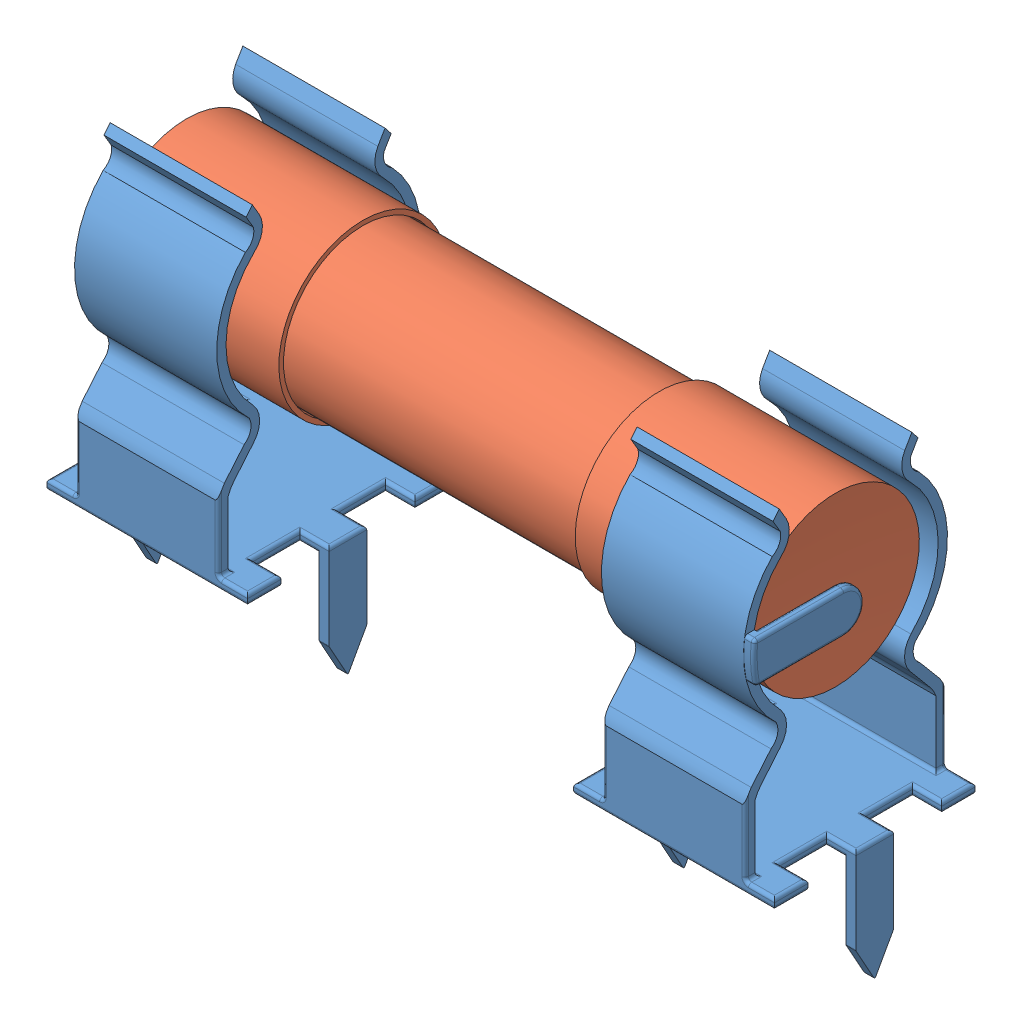
SolidWorks assembly SW3dPS-Full Fuse, configuration Default. Lengths in mm.
Overall size (22.1 12.9 6.21).
3 component instances, 2 part files, 8 mates.
Components (placement in the parent):
- SW3dPS-Full Fuse_Fuse Leg_2009-1: SW3dPS-Full Fuse_Fuse Leg_2009 [Default] at (8 0 0) x (1 0 0) z (0 1 0) size (6.1 6.2 12.9)
- SW3dPS-Full Fuse_Fuse Leg_2009-2: SW3dPS-Full Fuse_Fuse Leg_2009 [Default] at (-8 0 0) x (-1 0 0) z (0 1 0) size (6.1 6.2 12.9)
- SW3dPS-Full Fuse_Fuse Small 1A-1: SW3dPS-Full Fuse_Fuse Small 1A [Default] at (0 6.3 0) x (1 0 0) z (0 -1 0) size (19.91 5.21 5.19)
Mates (geometry in assembly coordinates):
- Distance1: distance = 16 mm anti-aligned: plane of SW3dPS-Full Fuse_Fuse Leg_2009-1; plane of SW3dPS-Full Fuse_Fuse Leg_2009-2
- Coincident2: coincident aligned: plane of SW3dPS-Full Fuse_Fuse Small 1A-1; plane of assembly through (0 0 0) normal (1 0 0)
- Concentric1: concentric aligned: circle of SW3dPS-Full Fuse_Fuse Leg_2009-1; circle of SW3dPS-Full Fuse_Fuse Small 1A-1
- Concentric2: concentric aligned: circle of SW3dPS-Full Fuse_Fuse Leg_2009-2; circle of SW3dPS-Full Fuse_Fuse Small 1A-1
- Coincident4: coincident anti-aligned: plane of SW3dPS-Full Fuse_Fuse Leg_2009-1 through (10.948 0 2.948) normal (0 -1 0); plane of assembly through (0 0 0) normal (0 1 0)
- Parallel1: parallel aligned: plane of SW3dPS-Full Fuse_Fuse Leg_2009-1 through (10.948 0.3 2.948) normal (0 1 0); plane of SW3dPS-Full Fuse_Fuse Leg_2009-2 through (-10.948 0.3 -2.948) normal (0 1 0)
- Distance3: distance = 8 mm aligned: plane of SW3dPS-Full Fuse_Fuse Leg_2009-1; plane of assembly through (0 0 0) normal (1 0 0)
- Coincident9: coincident aligned: plane of SW3dPS-Full Fuse_Fuse Small 1A-1 through (0 6.3 0) normal (0 0 1); plane of assembly through (0 0 0) normal (0 0 1)
